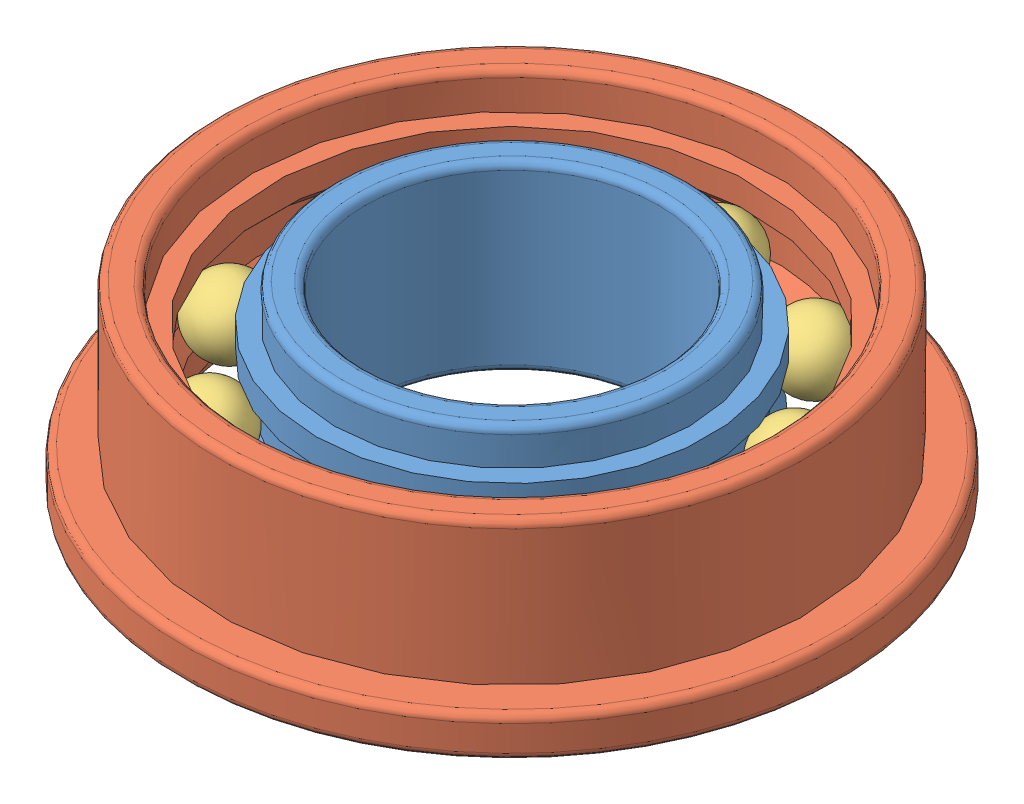
SolidWorks assembly F688ZZ_assembly, configuration Default. Lengths in mm.
Overall size (20.89 5 20.89).
12 component instances, 3 part files, 8 mates.
Components (placement in the parent):
- F688ZZ_shaft-1: F688ZZ_shaft [Default] at origin size (10.7 5 10.7)
- F688ZZ_Housing-1: F688ZZ_Housing [Default] x (0.984312 0 0.176438) z (-0.176438 0 0.984312) size (18 5 18)
- F688ZZ_Ball-1: F688ZZ_Ball [Default] at (5.5752 2.5 -2.1489) x (0.959238 0.232099 0.161224) z (-0.142462 -0.095558 0.985177) size (2 2 2)
- F688ZZ_Ball-20: F688ZZ_Ball [Default] at (3.2474 2.5 -5.0155) x (0.870805 0.232099 -0.433393) z (0.463818 -0.095558 0.880762) size (2 2 2)
- F688ZZ_Ball-21: F688ZZ_Ball [Default] at (-0.3209 2.5 -5.9664) x (0.449753 0.232099 -0.862469) z (0.892936 -0.095558 0.439926) size (2 2 2)
- F688ZZ_Ball-22: F688ZZ_Ball [Default] at (-3.7665 2.5 -4.6383) x (-0.143088 0.232099 -0.96211) z (0.980982 -0.095558 -0.168947) size (2 2 2)
- F688ZZ_Ball-23: F688ZZ_Ball [Default] at (-5.7735 2.5 -1.5385) x (-0.681275 0.232099 -0.694258) z (0.694326 -0.095558 -0.713288) size (2 2 2)
- F688ZZ_Ball-24: F688ZZ_Ball [Default] at (-5.5752 2.5 2.1489) x (-0.959238 0.232099 -0.161224) z (0.142462 -0.095558 -0.985177) size (2 2 2)
- F688ZZ_Ball-25: F688ZZ_Ball [Default] at (-3.2474 2.5 5.0155) x (-0.870805 0.232099 0.433393) z (-0.463818 -0.095558 -0.880762) size (2 2 2)
- F688ZZ_Ball-26: F688ZZ_Ball [Default] at (0.3209 2.5 5.9664) x (-0.449753 0.232099 0.862469) z (-0.892936 -0.095558 -0.439926) size (2 2 2)
- F688ZZ_Ball-27: F688ZZ_Ball [Default] at (3.7665 2.5 4.6383) x (0.143088 0.232099 0.96211) z (-0.980982 -0.095558 0.168947) size (2 2 2)
- F688ZZ_Ball-28: F688ZZ_Ball [Default] at (5.7735 2.5 1.5385) x (0.681275 0.232099 0.694258) z (-0.694326 -0.095558 0.713288) size (2 2 2)
Mates (geometry in assembly coordinates):
- Eş Merkezli1: concentric aligned: cylinder of F688ZZ_shaft-1 through (0 5 0) axis (0 -1 0) radius 5.35; cylinder of F688ZZ_Housing-1 through (0 5 0) axis (0 -1 0) radius 6.6
- Çakışık2: coincident aligned: plane of F688ZZ_shaft-1 through (0 0 0) normal (0 -1 0); plane of F688ZZ_Housing-1 through (0 0 0) normal (0 -1 0)
- Teğet1: tangent anti-aligned: cylinder of F688ZZ_shaft-1 through (0 0 0) axis (0 -1 0) radius 4.975; sphere of F688ZZ_Ball-1
- Teğet2: tangent anti-aligned: cone of F688ZZ_shaft-1 through (0 1.5 0) axis (0 1 0); sphere of F688ZZ_Ball-1
- Teğet3: tangent anti-aligned: cone of F688ZZ_shaft-1 through (0 2.9142 0) axis (0 -1 0); sphere of F688ZZ_Ball-1
- Teğet4: tangent aligned: cylinder of F688ZZ_Housing-1 through (0 0 0) axis (0 -1 0) radius 6.975; sphere of F688ZZ_Ball-1
- Teğet5: tangent aligned: cone of F688ZZ_Housing-1 through (0 2.0858 0) axis (0 -1 0); sphere of F688ZZ_Ball-1
- Teğet6: tangent aligned: cone of F688ZZ_Housing-1 through (0 4 0) axis (0 1 0); sphere of F688ZZ_Ball-1
